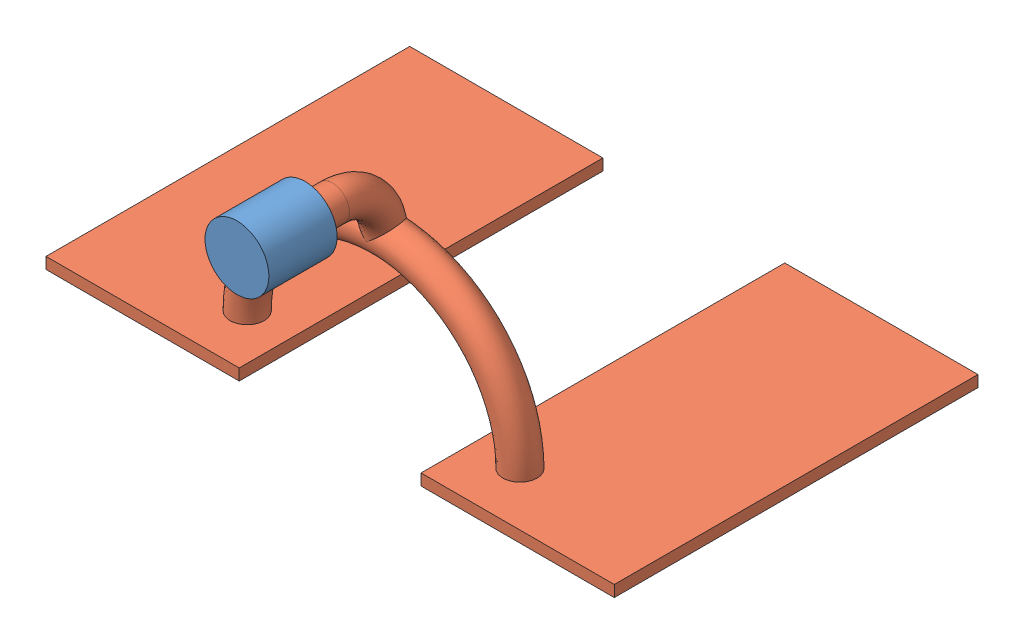
SolidWorks assembly Full_Restrictor, configuration Default. Lengths in mm.
Overall size (25 10.16 20.1).
2 component instances, 2 part files, 6 mates.
Components (placement in the parent):
- Lid_Restrictor-1: Lid_Restrictor [Default] at (0 8.5 10.1) x (1 0 0) z (0 0 -1) size (2.81 2.81 3)
- Restrictor-1: Restrictor [Default] at origin size (25 9.5 19.9)
Mates (geometry in assembly coordinates):
- Coincident1: coincident aligned: plane of assembly through (0 0 0) normal (1 0 0); plane of Restrictor-1 through (0 0 0) normal (1 0 0)
- Coincident2: coincident aligned: plane of Restrictor-1 through (0 0 0) normal (0 1 0)
- Coincident3: coincident aligned: plane of Restrictor-1 through (0 0 0) normal (0 0 1)
- Coincident5: coincident aligned: plane of Lid_Restrictor-1 through (0 8.5 10.1) normal (1 0 0)
- Concentric1: concentric aligned: circle of Lid_Restrictor-1; cylinder of Restrictor-1 through (0 8.5 9.9) axis (0 0 -1) radius 0.75
- Coincident6: coincident anti-aligned: plane of Lid_Restrictor-1 through (0 8.5 9.9) normal (0 0 -1); plane of Restrictor-1 through (0 8.5 9.9) normal (0 0 1)
